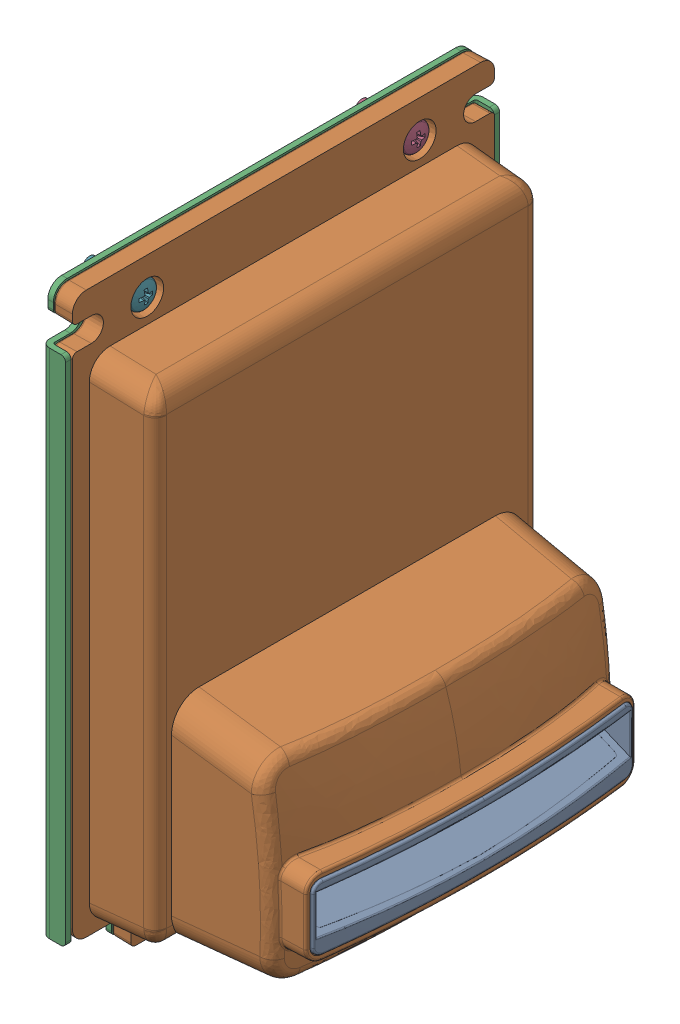
SolidWorks assembly Faceplate assembly^ST1-C BILL RECOGNIZER ASSY, configuration Default. Lengths in mm.
Overall size (56 128.3 94).
8 component instances, 4 part files, 0 mates.
Components (placement in the parent):
- Note Guide PCB ASSY-1-1: Note Guide PCB ASSY-1 [Default] at (-52.2 4 0) x (0 0 -1) z (1 0 0) size (70.85 37.99 28.59)
  - ASY-M-601281 R11 NG, 66mm Up Stacker-1: ASY-M-601281 R11 NG, 66mm Up Stacker [Default] at (0 -3.5 -53.4) size (70.85 37.99 28.59)
- ASY-M-601280 R6 Faceplate, 66mm Up Stacker-1: ASY-M-601280 R6 Faceplate, 66mm Up Stacker [Default] at (-52.2 4 0) x (0 0 -1) z (1 0 0) size (91.4 128.25 48.2)
- 721322 Panel Bracket-1: 721322 Panel Bracket [Default] at origin size (5.2 128.23 94)
- ASY-M-509081 Screw, Machine - M3 x 10 PH CR - ZP(Phillips Pan Head M3 x 10mm)-1: ASY-M-509081 Screw, Machine - M3 x 10 PH CR - ZP(Phillips Pan Head M3 x 10mm) [Default] at (-48.1 62 -29.5) x (-1 0 0) z (0 0.021465 -0.99977) size (12.4 6 6)
- ASY-M-509081 Screw, Machine - M3 x 10 PH CR - ZP(Phillips Pan Head M3 x 10mm)-2: ASY-M-509081 Screw, Machine - M3 x 10 PH CR - ZP(Phillips Pan Head M3 x 10mm) [Default] at (-48.1 -54 -12.7) x (-1 0 0) z (0 0.021465 -0.99977) size (12.4 6 6)
- ASY-M-509081 Screw, Machine - M3 x 10 PH CR - ZP(Phillips Pan Head M3 x 10mm)-3: ASY-M-509081 Screw, Machine - M3 x 10 PH CR - ZP(Phillips Pan Head M3 x 10mm) [Default] at (-48.1 -54 12.7) x (-1 0 0) z (0 0.021465 -0.99977) size (12.4 6 6)
- ASY-M-509081 Screw, Machine - M3 x 10 PH CR - ZP(Phillips Pan Head M3 x 10mm)-4: ASY-M-509081 Screw, Machine - M3 x 10 PH CR - ZP(Phillips Pan Head M3 x 10mm) [Default] at (-48.1 62 29.5) x (-1 0 0) z (0 -0.021465 0.99977) size (12.4 6 6)
